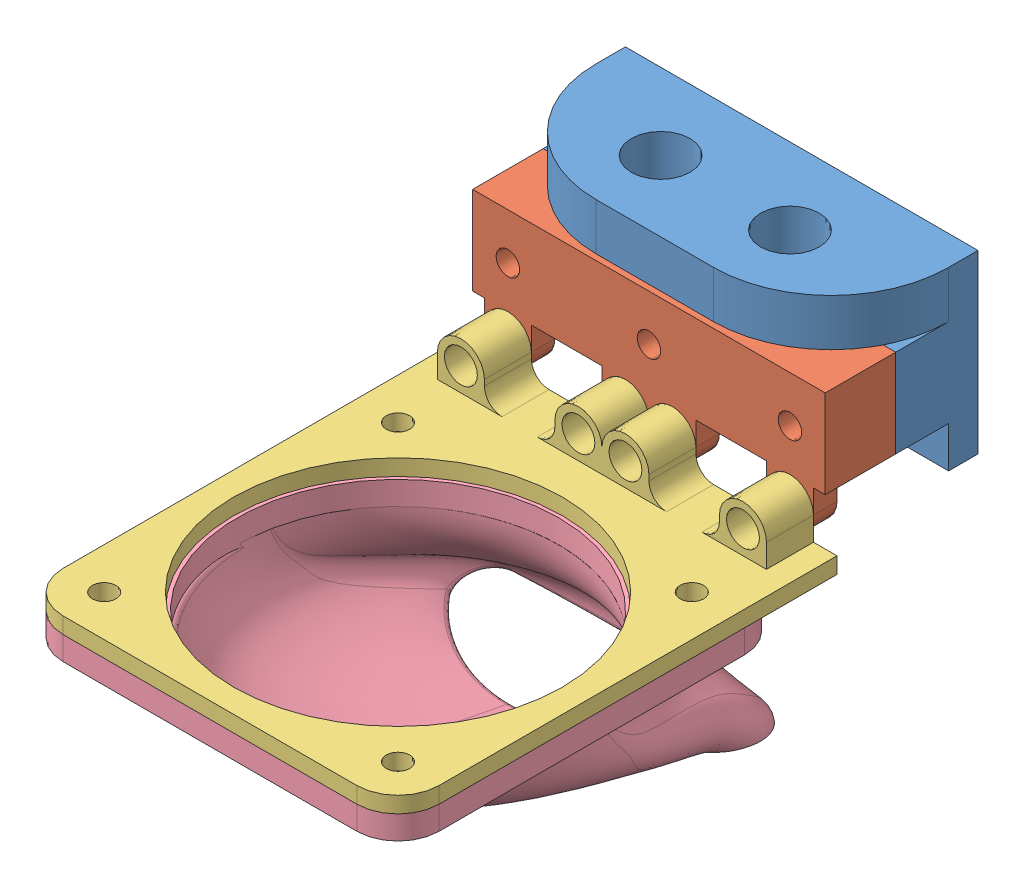
SolidWorks assembly Assieme1, configuration Default. Lengths in mm.
Overall size (150.43 62.26 108.06).
4 component instances, 4 part files, 4 mates.
Components (placement in the parent):
- supporto_1-1: supporto_1 [Default] at (-43.7434 73.8371 -13) size (81.89 30 40.72)
- supporto_2-1: supporto_2 [Default] at (-43.7434 73.8371 13) x (-1 0 0) z (0 0 -1) size (81.89 31.01 40.72)
- supporto ventola-1: supporto ventola [Default] at (-12.259 55.0806 13) size (64 14.75 74.7)
- ventola-1: ventola [Default] at (-43.7434 55.0806 55.7) x (0 0 -1) z (0 1 0) size (77.46 150.43 28.51)
Mates (geometry in assembly coordinates):
- Coincidente5: coincident: point of supporto_1-1; point of supporto_2-1
- Coincidente6: coincident anti-aligned: circle of supporto_2-1; circle of supporto ventola-1
- Concentrico3: concentric: circle of supporto ventola-1; circle of ventola-1
- Coincidente7: coincident aligned: line of supporto ventola-1 through (-68.7434 55.0806 87.7) axis (1 0 0); line of ventola-1 through (-68.7434 55.0806 87.7) axis (1 0 0)
